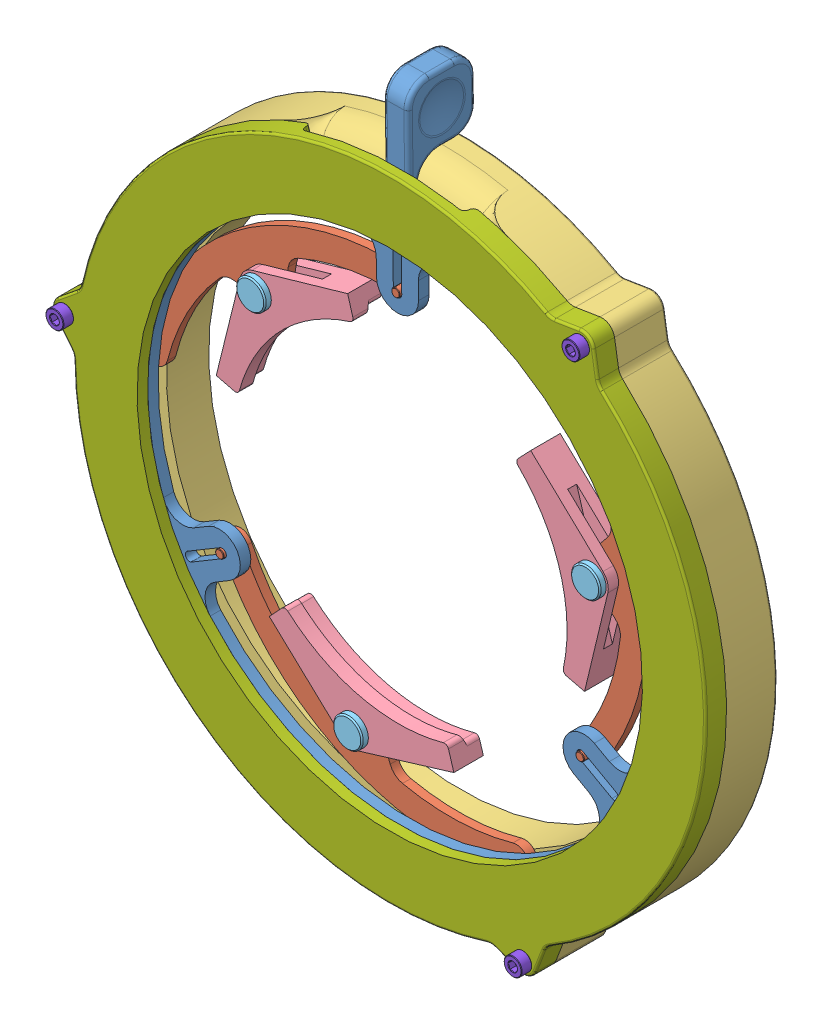
SolidWorks assembly MainAssembly, configuration Default. Lengths in mm.
Overall size (425.33 427.8 42.23).
19 component instances, 8 part files, 37 mates.
Components (placement in the parent):
- Rotatingring-1: Rotatingring [Default] at (-59.3949 31.4053 15.2372) x (0.999915 0.013021 0) z (0 0 1) size (280 325 32.23)
- Irisarm-1: Irisarm [Default] at (-127.7591 96.6148 11.2372) x (-0.811283 -0.584653 0) z (0 0 1) size (160.07 39 13)
- Irisarm-2: Irisarm [Default] at (31.2603 58.0057 11.2372) x (-0.100683 0.994919 0) z (0 0 1) size (160.07 39 13)
- Irisarm-3: Irisarm [Default] at (-81.6859 -60.4047 11.2372) x (0.911966 -0.410265 0) z (0 0 1) size (160.07 39 13)
- Staticring-1: Staticring [Default] at (-59.3949 31.4053 -8.7628) x (0.810362 -0.58593 0) z (0 0 1) size (300 311 24.85)
- clampingarc-1: clampingarc [Default] at (-84.4935 117.4334 6.1122) x (0.277393 -0.960757 0) z (-0.960757 -0.277393 0) size (49.68 14 77.94)
- clampingarc-2: clampingarc [Default] at (27.9934 10.1031 6.1122) x (-0.972399 0.233323 0) z (0.233323 0.972399 0) size (49.68 14 77.94)
- clampingarc-3: clampingarc [Default] at (-121.7235 -33.9033 6.1122) x (0.683176 0.730254 0) z (0.730254 -0.683176 0) size (49.68 14 77.94)
- 93131A320_METRIC CLEVIS PIN-1: 93131A320_METRIC CLEVIS PIN [93131A320] at (31.2603 58.0057 10.1122) x (0.368638 -0.929573 0) z (0 0 1) size (14 14 23)
- 93131A320_METRIC CLEVIS PIN-2: 93131A320_METRIC CLEVIS PIN [93131A320] at (-81.6859 -60.4047 10.1122) x (0.987753 -0.156027 0) z (0 0 1) size (14 14 23)
- 93131A320_METRIC CLEVIS PIN-3: 93131A320_METRIC CLEVIS PIN [93131A320] at (-127.7591 96.6148 10.1122) x (0.71303 0.701133 0) z (0 0 1) size (14 14 23)
- module24-1: module24 [Default] at (-85.486 47.412 269.3042) x (0.999719 0.023713 0) z (-0.023713 0.999719 0) (suppressed, hidden)
- 92375A008_TYPE 316 SS REUSABLE HAIRPIN COTTER PIN-1: 92375A008_TYPE 316 SS REUSABLE HAIRPIN COTTER PIN [92375A008] at (-140.8712 83.7215 4.1122) x (-0.247712 0.251916 0.935509) z (-0.71303 -0.701133 0) size (1.19 9.74 41.27)
- 92375A008_TYPE 316 SS REUSABLE HAIRPIN COTTER PIN-2: 92375A008_TYPE 316 SS REUSABLE HAIRPIN COTTER PIN [92375A008] at (-99.1741 -57.6422 4.1122) x (-0.015799 -0.100017 0.99486) z (-0.987753 0.156027 0) size (1.19 9.74 41.27)
- 92375A008_TYPE 316 SS REUSABLE HAIRPIN COTTER PIN-3: 92375A008_TYPE 316 SS REUSABLE HAIRPIN COTTER PIN [92375A008] at (24.8446 74.184 4.1122) x (0.168824 0.06695 0.98337) z (-0.368638 0.929573 0) size (1.19 9.74 41.27)
- keeperring-1: keeperring [Default] at (-59.3949 31.4053 15.2372) x (0.810362 -0.58593 0) z (0 0 1) size (300 311 10.14)
- 91290A242_BLACK-OXIDE CLASS 12.9 SOCKET HEAD CAP SCREW-1: 91290A242_BLACK-OXIDE CLASS 12.9 SOCKET HEAD CAP SCREW [91290A242] at (31.4242 157.0114 5.2372) x (-0.909103 0.416572 0) z (0 0 -1) size (8.5 8.5 25.47)
- 91290A242_BLACK-OXIDE CLASS 12.9 SOCKET HEAD CAP SCREW-2: 91290A242_BLACK-OXIDE CLASS 12.9 SOCKET HEAD CAP SCREW [91290A242] at (3.9736 -110.0494 5.2372) x (-0.923728 -0.383049 0) z (0 0 -1) size (8.5 8.5 25.47)
- 91290A242_BLACK-OXIDE CLASS 12.9 SOCKET HEAD CAP SCREW-3: 91290A242_BLACK-OXIDE CLASS 12.9 SOCKET HEAD CAP SCREW [91290A242] at (-213.5825 47.2539 5.2372) x (-0.923728 -0.383049 0) z (0 0 -1) size (8.5 8.5 25.47)
Mates (geometry in assembly coordinates):
- Concentric2: concentric aligned: cylinder of Irisarm-3 through (-8.7001 -81.7585 8.2372) axis (0 0 1) radius 2; circle of Staticring-1
- Coincident3: coincident anti-aligned: plane of Irisarm-3 through (-81.6859 -60.4047 11.2372) normal (0 0 -1); plane of Staticring-1 through (-59.3949 31.4053 11.2372) normal (0 0 1)
- Coincident4: coincident anti-aligned: plane of Rotatingring-1 through (-59.3949 31.4053 15.2372) normal (0 0 -1); plane of Irisarm-3 through (-81.6859 -60.4047 15.2372) normal (0 0 1)
- Slot1: slot anti-aligned: plane of Rotatingring-1 through (-58.3724 29.6864 -27.5515) normal (-0.511234 0.859442 0); cylinder of Irisarm-3 through (-144.279 -19.0876 21.2372) axis (0 0 -1) radius 2; cylinder of Rotatingring-1 through (-159.439 -28.1054 -27.5515) axis (0 0 1) radius 2
- Concentric3: concentric aligned: circle of Irisarm-3; circle of clampingarc-3
- Slot2: slot anti-aligned: cylinder of Irisarm-2 through (26.7753 -16.8601 21.2372) axis (0 0 -1) radius 2; plane of Rotatingring-1 through (-60.3723 29.6604 -27.5515) normal (0.488681 0.872462 0); cylinder of Rotatingring-1 through (42.1649 -25.4801 -27.5515) axis (0 0 1) radius 2
- Coincident7: coincident anti-aligned: plane of Rotatingring-1 through (-59.3949 31.4053 15.2372) normal (0 0 -1); plane of Irisarm-2 through (31.2603 58.0057 15.2372) normal (0 0 1)
- Concentric5: concentric aligned: cylinder of Irisarm-2 through (13.2604 131.8901 8.2372) axis (0 0 1) radius 2; cylinder of Staticring-1 through (13.2604 131.8901 7.7372) axis (0 0 1) radius 2
- Slot3: slot anti-aligned: cylinder of Irisarm-1 through (-60.6809 130.1635 21.2372) axis (0 0 -1) radius 2; plane of Rotatingring-1 through (-57.3951 31.4313 -20.8183) normal (-0.999915 -0.013021 0); cylinder of Rotatingring-1 through (-60.9106 147.8014 -20.8183) axis (0 0 1) radius 2
- Coincident8: coincident anti-aligned: plane of Rotatingring-1 through (-59.3949 31.4053 15.2372) normal (0 0 -1); plane of Irisarm-1 through (-127.7591 96.6148 15.2372) normal (0 0 1)
- Concentric6: concentric aligned: cylinder of Irisarm-1 through (-182.745 44.0842 8.2372) axis (0 0 1) radius 2; cylinder of Staticring-1 through (-182.745 44.0842 7.7372) axis (0 0 1) radius 2
- Concentric8: concentric anti-aligned: cylinder of Irisarm-2 through (31.2603 58.0057 15.2372) axis (0 0 -1) radius 4; cylinder of clampingarc-2 through (31.2603 58.0057 6.1122) axis (0 0 1) radius 4
- Coincident14: coincident anti-aligned: plane of Irisarm-3 through (-81.6859 -60.4047 15.2372) normal (0 0 1); plane of clampingarc-3 through (-123.704 -42.4192 15.2372) normal (0 0 -1)
- Coincident15: coincident anti-aligned: plane of clampingarc-3 through (-37.2039 -43.957 20.1122) normal (0 0 1); plane of 93131A320_METRIC CLEVIS PIN-2 through (-81.6859 -60.4047 20.1122) normal (0 0 -1)
- Concentric9: concentric anti-aligned: cylinder of clampingarc-3 through (-81.6859 -60.4047 6.1122) axis (0 0 1) radius 4; cylinder of 93131A320_METRIC CLEVIS PIN-2 through (-81.6859 -60.4047 20.1122) axis (0 0 -1) radius 4
- Concentric10: concentric anti-aligned: cylinder of Irisarm-2 through (31.2603 58.0057 15.2372) axis (0 0 -1) radius 4; cylinder of clampingarc-2 through (31.2603 58.0057 6.1122) axis (0 0 1) radius 4
- Coincident16: coincident anti-aligned: plane of Irisarm-2 through (31.2603 58.0057 15.2372) normal (0 0 1); plane of clampingarc-2 through (36.3762 12.5873 15.2372) normal (0 0 -1)
- Coincident17: coincident aligned: circle of Irisarm-1; cylinder of clampingarc-1 through (-127.7591 96.6148 6.1122) axis (0 0 1) radius 4
- Coincident18: coincident anti-aligned: plane of Irisarm-1 through (-127.7591 96.6148 15.2372) normal (0 0 1); plane of clampingarc-1 through (-90.7938 123.4954 15.2372) normal (0 0 -1)
- Concentric11: concentric anti-aligned: cylinder of clampingarc-2 through (31.2603 58.0057 6.1122) axis (0 0 1) radius 4; cylinder of 93131A320_METRIC CLEVIS PIN-1 through (31.2603 58.0057 20.1122) axis (0 0 -1) radius 4
- Coincident19: coincident aligned: plane of clampingarc-2 through (-5.0121 88.5587 20.1122) normal (0 0 1); circle of 93131A320_METRIC CLEVIS PIN-1
- Concentric12: concentric anti-aligned: cylinder of clampingarc-1 through (-127.7591 96.6148 6.1122) axis (0 0 1) radius 4; cylinder of 93131A320_METRIC CLEVIS PIN-3 through (-127.7591 96.6148 20.1122) axis (0 0 -1) radius 4
- Coincident20: coincident anti-aligned: plane of clampingarc-1 through (-136.4104 49.9851 20.1122) normal (0 0 1); plane of 93131A320_METRIC CLEVIS PIN-3 through (-127.7591 96.6148 20.1122) normal (0 0 -1)
- Concentric13: concentric anti-aligned: circle of Rotatingring-1; cylinder of module24-1/moduleRing-1 through (-59.3949 31.4053 592.515) axis (0 0 -1) radius 76.2
- Concentric14: concentric anti-aligned: cylinder of 93131A320_METRIC CLEVIS PIN-1 through (28.6799 64.5127 4.1122) axis (0.368638 -0.929573 0) radius 1; cylinder of 92375A008_TYPE 316 SS REUSABLE HAIRPIN COTTER PIN-3 through (38.4507 39.874 4.1122) axis (-0.368638 0.929573 0) radius 0.5953
- Concentric16: concentric anti-aligned: cylinder of 93131A320_METRIC CLEVIS PIN-2 through (-88.6002 -59.3125 4.1122) axis (0.987753 -0.156027 0) radius 1; cylinder of 92375A008_TYPE 316 SS REUSABLE HAIRPIN COTTER PIN-2 through (-62.7168 -63.4011 4.1122) axis (-0.987753 0.156027 0) radius 0.5953
- Concentric18: concentric anti-aligned: cylinder of 93131A320_METRIC CLEVIS PIN-3 through (-132.7504 91.7069 4.1122) axis (0.71303 0.701133 0) radius 1; cylinder of 92375A008_TYPE 316 SS REUSABLE HAIRPIN COTTER PIN-1 through (-114.5537 109.5999 4.1122) axis (-0.71303 -0.701133 0) radius 0.5953
- Concentric19: concentric aligned: circle of Rotatingring-1; circle of Staticring-1
- Concentric20: concentric aligned: circle of Rotatingring-1; circle of keeperring-1
- Concentric21: concentric aligned: circle of Staticring-1; circle of keeperring-1
- Coincident22: coincident anti-aligned: plane of Staticring-1 through (-59.3949 31.4053 15.2372) normal (0 0 1); plane of keeperring-1 through (-59.3949 31.4053 15.2372) normal (0 0 -1)
- Concentric22: concentric anti-aligned: circle of keeperring-1; circle of 91290A242_BLACK-OXIDE CLASS 12.9 SOCKET HEAD CAP SCREW-3
- Coincident23: coincident anti-aligned: plane of keeperring-1 through (-59.3949 31.4053 25.2372) normal (0 0 1); plane of 91290A242_BLACK-OXIDE CLASS 12.9 SOCKET HEAD CAP SCREW-3 through (-213.5825 47.2539 25.2372) normal (0 0 -1)
- Concentric23: concentric anti-aligned: circle of keeperring-1; circle of 91290A242_BLACK-OXIDE CLASS 12.9 SOCKET HEAD CAP SCREW-2
- Coincident24: coincident anti-aligned: plane of keeperring-1 through (-59.3949 31.4053 25.2372) normal (0 0 1); plane of 91290A242_BLACK-OXIDE CLASS 12.9 SOCKET HEAD CAP SCREW-2 through (3.9736 -110.0494 25.2372) normal (0 0 -1)
- Concentric24: concentric anti-aligned: circle of keeperring-1; circle of 91290A242_BLACK-OXIDE CLASS 12.9 SOCKET HEAD CAP SCREW-1
- Coincident25: coincident anti-aligned: plane of keeperring-1 through (-59.3949 31.4053 25.2372) normal (0 0 1); plane of 91290A242_BLACK-OXIDE CLASS 12.9 SOCKET HEAD CAP SCREW-1 through (31.4242 157.0114 25.2372) normal (0 0 -1)
